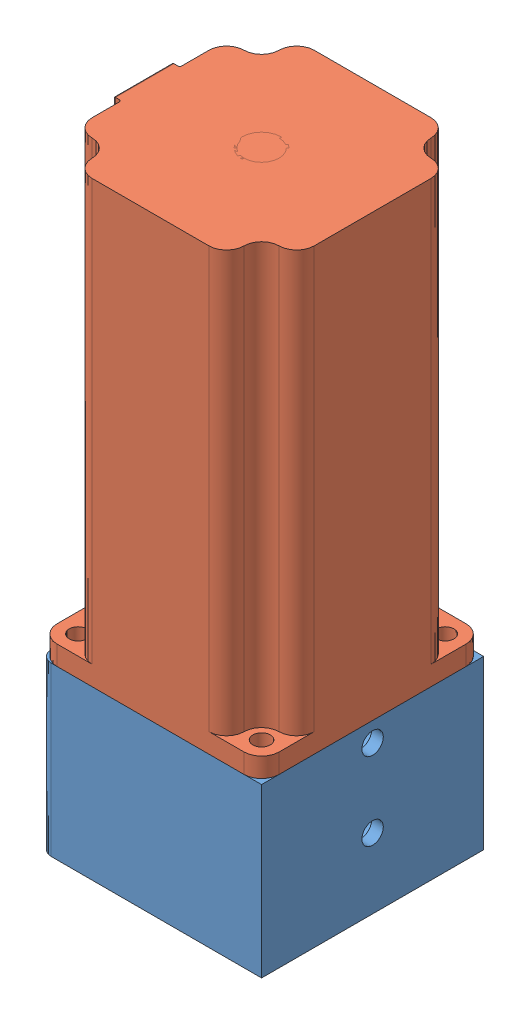
SolidWorks assembly Stepper Assembly, configuration Left. Lengths in mm.
Overall size (59 156 57).
3 component instances, 3 part files, 8 mates.
Components (placement in the parent):
- Stepper Mount^XGantry_XY Gantry_Sp33der-1: Stepper Mount^XGantry_XY Gantry_Sp33der [Left] at origin size (57 43 57)
- Nema 23 113mm body -1: Nema 23 113mm body  [Default] at (0 156 0) x (0 0 1) z (0 -1 0) size (57 59 137)
- GT2_T24_W12_Ø10-1: GT2_T24_W12_Ø10 [Default] at (0 19 0) x (-0.694269 0 0.719715) z (0 1 0) size (20 20 21.8)
Mates (geometry in assembly coordinates):
- Concentric2: concentric aligned: cylinder of Nema 23 113mm body -1 through (0 -19.1421 0) axis (0 1 0) radius 5; cylinder of GT2_T24_W12_Ø10-1 through (0 19 0) axis (0 1 0) radius 5
- Coincident3: coincident aligned: plane of Nema 23 113mm body -1 through (0 19 0) normal (0 -1 0); plane of GT2_T24_W12_Ø10-1 through (0 19 0) normal (0 -1 0)
- Coincident4: coincident anti-aligned: plane of Stepper Mount^XGantry_XY Gantry_Sp33der-1 through (0 43 0) normal (0 1 0); plane of Nema 23 113mm body -1 through (0 43 0) normal (0 -1 0)
- Coincident5: coincident aligned: plane of Stepper Mount^XGantry_XY Gantry_Sp33der-1 through (-28.5 13 -28.5) normal (0 0 -1); plane of Nema 23 113mm body -1 through (-28.5 43 -28.5) normal (0 0 -1)
- Coincident6: coincident aligned: plane of Stepper Mount^XGantry_XY Gantry_Sp33der-1 through (-28.5 13 -28.5) normal (-1 0 0); plane of Nema 23 113mm body -1 through (-28.5 43 -28.5) normal (-1 0 0)
- Coincident7: coincident aligned: plane of Stepper Mount^XGantry_XY Gantry_Sp33der-1 through (0 0 0) normal (0 0 1)
- Coincident8: coincident aligned: plane of Stepper Mount^XGantry_XY Gantry_Sp33der-1 through (0 0 0) normal (0 1 0)
- Coincident9: coincident aligned: plane of Stepper Mount^XGantry_XY Gantry_Sp33der-1 through (0 0 0) normal (1 0 0)
